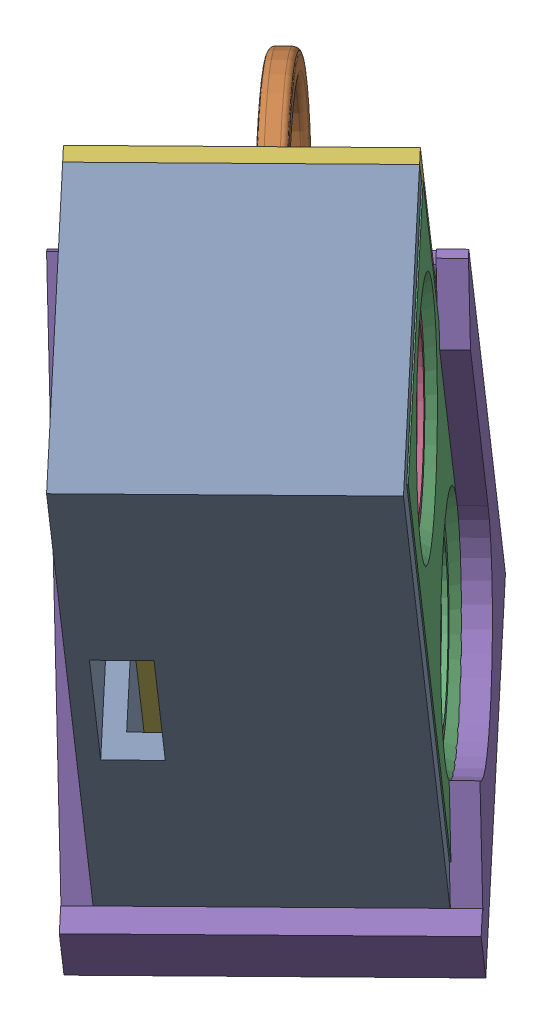
SolidWorks assembly 2.2.2.3_Caja_Ultrasonido, configuration Predeterminado. Lengths in mm.
Overall size (50.29 75.57 55.67).
6 component instances, 6 part files, 15 mates.
Components (placement in the parent):
- 2.1.2.2.3_Cubierta_Posterior-1: 2.1.2.2.3_Cubierta_Posterior [Predeterminado] at (89.0125 -31.8608 0.2222) x (-0.247516 -0.911396 -0.328775) z (0.748898 0.035331 -0.661743) size (52.81 23.68 22)
- 2.1.2.2.1_Manija-1: 2.1.2.2.1_Manija [Predeterminado] at (88.4905 -14.7597 21.6451) x (0.614726 -0.410011 0.673798) z (0.748898 0.035331 -0.661743) size (42.87 46.77 2.06)
- 2.1.2.2.2_Cubierta_Frontal-1: 2.1.2.2.2_Cubierta_Frontal [Predeterminado] at (78.3032 -32.366 9.6851) x (0.247516 0.911396 0.328775) z (0.614726 -0.410011 0.673798) size (48.81 9.5 21.68)
- HC-SR04.stp-1: HC-SR04.stp [Predeterminado] at (75.213 -29.0582 6.2192) x (-0.247516 -0.911396 -0.328775) z (0.748898 0.035331 -0.661743) size (45.62 20.4 15.39)
- 2.1.2.2.5_Sujetador-1: 2.1.2.2.5_Sujetador [Predeterminado] at (82.4771 -55.9253 -8.4588) x (-0.748898 -0.035331 0.661743) z (-0.247516 -0.911396 -0.328775) size (26 28.88 48.33)
- 2.1.2.2.4_Cubierta_Superior-1: 2.1.2.2.4_Cubierta_Superior [Predeterminado] at (65.6879 -24.0053 -3.9942) x (-0.247516 -0.911396 -0.328775) z (-0.614726 0.410011 -0.673798) size (52.81 22 15.2)
Mates (geometry in assembly coordinates):
- Coincidente2: coincident anti-aligned: plane of 2.1.2.2.3_Cubierta_Posterior-1 through (89.0133 -43.7792 -9.5766) normal (-0.068819 0.823131 0.563666); plane of 2.1.2.2.2_Cubierta_Frontal-1 through (78.0785 -48.5293 -3.9751) normal (0.068819 -0.823131 -0.563666)
- Coincidente3: coincident anti-aligned: plane of 2.1.2.2.3_Cubierta_Posterior-1 through (95.9853 -18.1074 -0.3158) normal (-0.523497 -0.851075 -0.040283); plane of 2.1.2.2.2_Cubierta_Frontal-1 through (87.6217 -13.3897 8.7011) normal (0.523497 0.851075 0.040283)
- Coincidente4: coincident anti-aligned: plane of 2.1.2.2.3_Cubierta_Posterior-1 through (81.6136 -10.8171 21.6845) normal (-0.614726 0.410011 -0.673798); plane of 2.1.2.2.2_Cubierta_Frontal-1 through (94.4198 -10.2129 10.3687) normal (0.614726 -0.410011 0.673798)
- Coincidente6: coincident anti-aligned: plane of 2.1.2.2.3_Cubierta_Posterior-1 through (58.2614 -28.5081 -3.3947) normal (0.748898 0.035331 -0.661743); plane of 2.1.2.2.4_Cubierta_Superior-1 through (69.7127 -29.9616 9.4872) normal (-0.748898 -0.035331 0.661743)
- Coincidente7: coincident anti-aligned: plane of 2.1.2.2.3_Cubierta_Posterior-1 through (64.2298 -17.3778 -2.067) normal (-0.247516 -0.911396 -0.328775); plane of 2.1.2.2.4_Cubierta_Superior-1 through (75.8567 -23.9919 7.5145) normal (0.247516 0.911396 0.328775)
- Coincidente8: coincident anti-aligned: plane of 2.1.2.2.3_Cubierta_Posterior-1 through (55.7076 -48.2324 -9.6311) normal (-0.614726 0.410011 -0.673798); plane of 2.1.2.2.4_Cubierta_Superior-1 through (65.6879 -24.0053 -3.9942) normal (0.614726 -0.410011 0.673798)
- Coincidente9: coincident anti-aligned: plane of 2.1.2.2.3_Cubierta_Posterior-1 through (70.2672 -57.9434 6.3276) normal (-0.247516 -0.911396 -0.328775); plane of 2.1.2.2.5_Sujetador-1 through (82.4771 -55.9253 -8.4588) normal (0.247516 0.911396 0.328775)
- Coincidente10: coincident anti-aligned: plane of 2.1.2.2.3_Cubierta_Posterior-1 through (72.5367 -32.6381 14.7806) normal (-0.748898 -0.035331 0.661743); plane of 2.1.2.2.5_Sujetador-1 through (66.0013 -56.7026 6.0996) normal (0.748898 0.035331 -0.661743)
- Concéntrica1: concentric aligned: cylinder of 2.1.2.2.1_Manija-1 through (72.4973 -39.8134 -4.6878) axis (-0.748898 -0.035331 0.661743) radius 7.95; cylinder of HC-SR04.stp-1 through (79.1241 -39.5007 -10.5434) axis (-0.748898 -0.035331 0.661743) radius 7.9502
- Concéntrica5: concentric: cylinder of 2.1.2.2.1_Manija-1 through (78.908 -16.2082 3.8275) axis (-0.748898 -0.035331 0.661743) radius 7.95; cylinder of HC-SR04.stp-1 through (85.5305 -15.9114 -2.0338) axis (-0.748898 -0.035331 0.661743) radius 7.9502
- Coincidente1: coincident anti-aligned: plane of 2.1.2.2.1_Manija-1 through (70.9995 -39.884 -3.3643) normal (-0.748898 -0.035331 0.661743); plane of HC-SR04.stp-1 through (69.0279 -28.2907 -4.9766) normal (0.748898 0.035331 -0.661743)
- Coincidente5: coincident anti-aligned: plane of 2.1.2.2.1_Manija-1 through (72.4973 -39.8134 -4.6878) normal (0.748898 0.035331 -0.661743); plane of 2.1.2.2.2_Cubierta_Frontal-1 through (78.908 -16.2082 3.8275) normal (-0.748898 -0.035331 0.661743)
- Concéntrica7: concentric aligned: cylinder of 2.1.2.2.1_Manija-1 through (78.908 -16.2082 3.8275) axis (-0.748898 -0.035331 0.661743) radius 10.4359; cylinder of 2.1.2.2.2_Cubierta_Frontal-1 through (84.5247 -15.9432 -1.1356) axis (-0.748898 -0.035331 0.661743) radius 7.95
- Concéntrica6: concentric aligned: cylinder of 2.1.2.2.2_Cubierta_Frontal-1 through (78.114 -39.5484 -9.6508) axis (-0.748898 -0.035331 0.661743) radius 7.95; cylinder of HC-SR04.stp-1 through (79.1241 -39.5007 -10.5434) axis (-0.748898 -0.035331 0.661743) radius 7.9502
- Concéntrica8: concentric aligned: cylinder of 2.1.2.2.5_Sujetador-1 through (79.5369 -39.4812 -10.9082) axis (0.748898 0.035331 -0.661743) radius 9.1047; cylinder of HC-SR04.stp-1 through (70.9256 -39.8875 -3.299) axis (0.748898 0.035331 -0.661743) radius 7.1236
